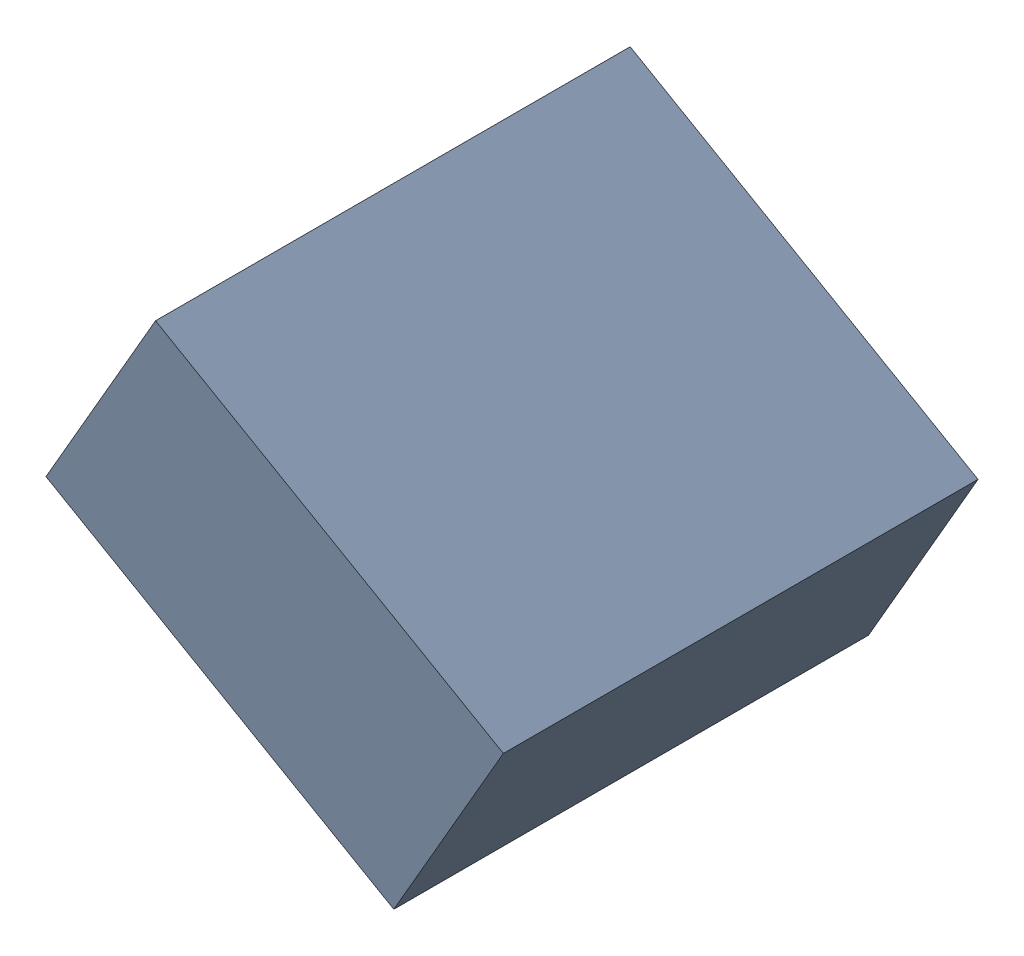
SolidWorks assembly C22_TDA6, configuration Standard. Lengths in mm.
Overall size (1.25 1.07 1.3).
2 component instances, 1 part files, 0 mates.
Components (placement in the parent):
- 885543056-1: 885543056 [Standard] at (-47.5534 24.6274 0) size (1.25 1.07 1.3)
  - Extruded_23-1: Extruded_23 [Standard] at origin size (1.25 1.07 1.3)
